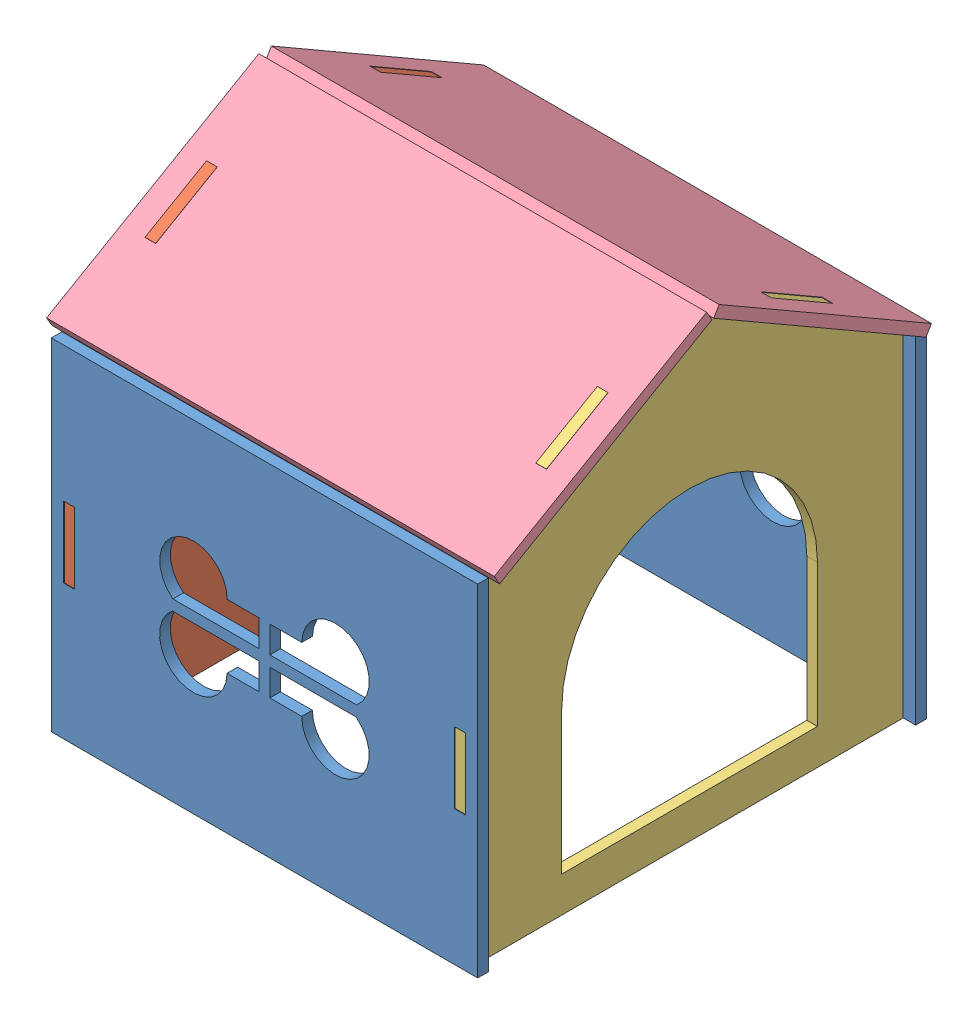
SolidWorks assembly Doggy house, configuration Predeterminado. Lengths in mm.
Overall size (630 665.91 631.25).
6 component instances, 4 part files, 13 mates.
Components (placement in the parent):
- Wall-1: Wall [Predeterminado] at (-46.2997 -15.3402 492.5) size (600 480 15)
- Back-2: Back [Predeterminado] at (-313.7997 -15.3402 191.7868) x (0 0 1) z (0 -1 0) size (630 15 653.21)
- Wall-2: Wall [Predeterminado] at (-46.2997 -15.3402 -123.7467) size (600 480 15)
- Entrance-1: Entrance [Predeterminado] at (236.2003 -15.3402 191.8563) x (0 0 1) z (0 -1 0) size (630 15 653.21)
- Roof-2: Roof [Predeterminado] at (-46.2997 311.3314 40.9327) x (1 0 0) z (0 0.5 0.866025) size (630 15 345)
- Roof-3: Roof [Predeterminado] at (-46.2997 310.712 342.2832) x (1 0 0) z (0 -0.5 0.866025) size (630 15 345)
Mates (geometry in assembly coordinates):
- Width1: width anti-aligned: plane of Back-2 through (-328.7997 34.6598 491.7868) normal (0 1 0); plane of Back-2 through (-328.7997 -65.3402 506.7868) normal (0 -1 0); plane of Wall-1 through (-328.7997 34.6598 492.499) normal (0 -1 0); plane of Wall-1 through (-328.7997 -65.3402 492.499) normal (0 1 0)
- Width2: width anti-aligned: plane of Back-2 through (-313.7997 -15.3402 191.7868) normal (1 0 0); plane of Back-2 through (-328.7997 -15.3402 191.7868) normal (-1 0 0); plane of Wall-1 through (-313.7997 -65.3402 492.499) normal (-1 0 0); plane of Wall-1 through (-328.7997 -65.3402 492.499) normal (1 0 0)
- Width3: width anti-aligned: plane of Entrance-1 through (221.2003 34.6598 491.8563) normal (0 1 0); plane of Entrance-1 through (221.2003 -65.3402 506.8563) normal (0 -1 0); plane of Wall-1 through (221.2003 34.6598 492.499) normal (0 -1 0); plane of Wall-1 through (221.2003 -65.3402 492.499) normal (0 1 0)
- Width4: width anti-aligned: plane of Entrance-1 through (236.2003 -15.3402 191.8563) normal (1 0 0); plane of Entrance-1 through (221.2003 -15.3402 191.8563) normal (-1 0 0); plane of Wall-1 through (236.2003 -65.3402 492.499) normal (-1 0 0); plane of Wall-1 through (221.2003 -65.3402 492.499) normal (1 0 0)
- Width5: width anti-aligned: plane of Entrance-1 through (221.2003 34.6598 -108.1437) normal (0 1 0); plane of Entrance-1 through (221.2003 -65.3402 -123.1437) normal (0 -1 0); plane of Wall-2 through (221.2003 34.6598 -123.7477) normal (0 -1 0); plane of Wall-2 through (221.2003 -65.3402 -123.7477) normal (0 1 0)
- Width6: width anti-aligned: plane of Entrance-1 through (236.2003 -15.3402 191.8563) normal (1 0 0); plane of Entrance-1 through (221.2003 -15.3402 191.8563) normal (-1 0 0); plane of Wall-2 through (236.2003 -65.3402 -123.7477) normal (-1 0 0); plane of Wall-2 through (221.2003 -65.3402 -123.7477) normal (1 0 0)
- Lock1: lock: unknown of Wall-1; unknown of Back-2
- Lock2: lock: unknown of Wall-1; unknown of Entrance-1
- Lock3: lock: unknown of Wall-2; unknown of Entrance-1
- Width11: width anti-aligned: plane of Roof-2 through (-328.7997 286.3306 -2.3681) normal (0 0.5 0.866025); plane of Roof-2 through (-328.7997 336.3306 84.2345) normal (0 -0.5 -0.866025); plane of Back-2 through (-328.7997 285.9098 -2.1251) normal (0 -0.5 -0.866025); plane of Back-2 through (-328.7997 348.9001 76.9774) normal (0 0.5 0.866025)
- Width12: width anti-aligned: plane of Roof-2 through (-328.7997 336.3306 84.2345) normal (1 0 0); plane of Roof-2 through (-313.7997 336.3306 84.2345) normal (-1 0 0); plane of Back-2 through (-328.7997 -15.3402 191.7868) normal (-1 0 0); plane of Back-2 through (-313.7997 -15.3402 191.7868) normal (1 0 0)
- Width13: width aligned: plane of Roof-3 through (-328.7997 335.7112 298.9815) normal (0 -0.5 0.866025); plane of Back-2 through (-328.7997 285.7112 385.584) normal (0 0.5 -0.866025); plane of Roof-3 through (-328.7997 285.9098 385.6987) normal (0 -0.5 0.866025); plane of Back-2 through (-328.7997 348.9001 306.5961) normal (0 0.5 -0.866025)
- Width14: width anti-aligned: plane of Roof-3 through (-313.7997 285.7112 385.584) normal (-1 0 0); plane of Back-2 through (-328.7997 285.7112 385.584) normal (1 0 0); plane of Roof-3 through (-313.7997 -15.3402 191.7868) normal (1 0 0); plane of Back-2 through (-328.7997 -15.3402 191.7868) normal (-1 0 0)
